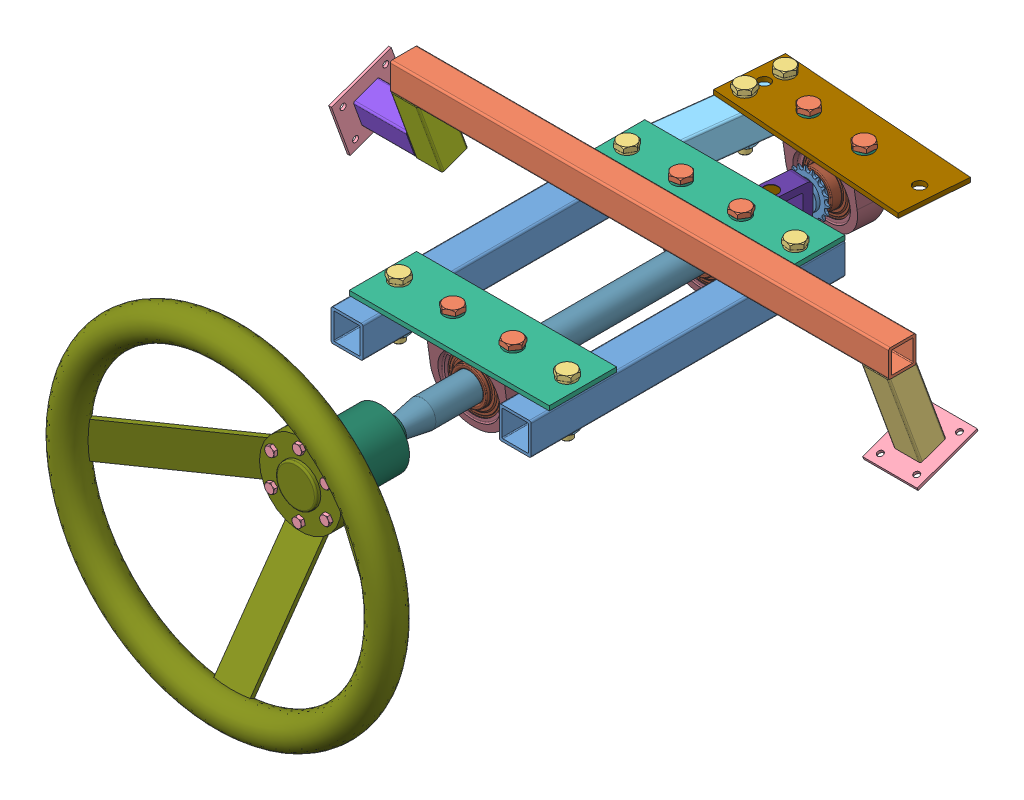
SolidWorks assembly Kolumna kierownicza uproszczenie, configuration Domyślna. Lengths in mm.
Overall size (624 386.49 780.76).
85 component instances, 24 part files, 119 mates.
Components (placement in the parent):
- belka nośna wzdłóżna-1: belka nośna wzdłóżna [Domyślna] at (-21.9242 46.9041 -172.5) size (35 35 345)
- belka nośna wzdłóżna-2: belka nośna wzdłóżna [Domyślna] at (163.0758 46.9041 -172.5) size (35 35 345)
- belka nośna poprzeczna-1: belka nośna poprzeczna [Domyślna] at (-192.6858 81.9041 -63.5) x (0 0 -1) z (1 0 0) size (30 30 548)
- belka wspornikowa pionowa-1: belka wspornikowa pionowa [Domyślna] at (352.3142 -9.754 -112.8235) x (0 0.34202 -0.939693) z (0 0.939693 0.34202) size (30 30 103)
- blacha mocująca-1: blacha mocująca [Domyślna] at (-250.6858 42.1744 -56.6769) x (0 0.34202 -0.939693) z (0 0.939693 0.34202) size (70 3 60)
- blacha mocująca-2: blacha mocująca [Domyślna] at (310.3142 -21.7247 -79.9342) x (0 0.34202 -0.939693) z (-1 0 0) size (70 3 60)
- brlka nośna skośna-1: brlka nośna skośna [Domyślna] at (12.5071 46.9041 -309.3237) x (0.992546 0 0.121869) z (-0.121869 0 0.992546) size (35 35 140)
- blacha nośna-1: blacha nośna [Domyślna] at (-21.9242 81.9041 152.5) size (220 5 74)
- blacha nośna-2: blacha nośna [Domyślna] at (-21.9242 81.9041 -98.5) size (220 5 74)
- belka wspornikowa pionowa mała-1: belka wspornikowa pionowa mała [Domyślna] at (-165.6858 11.859 -104.957) x (0 0.34202 -0.939693) z (0 0.939693 0.34202) size (30 30 80)
- belka poprzeczna mała-1: belka poprzeczna mała [Domyślna] at (-250.6858 16.9893 -119.0524) x (0 0.939693 0.34202) z (1 0 0) size (30 30 58)
- blacha nośna wachliwa-1: blacha nośna wachliwa [Domyślna] at (-12.9041 81.9041 -239.0734) x (0.997266 0 0.073897) z (-0.073897 0 0.997266) size (220 5 74)
- SKF_UCPA 206-1: SKF_UCPA 206 [Default] at (88.0758 39.1041 115.5) x (0 0 1) z (1 0 0) size (41.71 84.01 93.51)
  - 30-62-38.1-18-ucpa--9.525-46.5-1: 30-62-38.1-18-ucpa--9.525-46.5 [Default] at (0 39.6902 16.4402) x (1 0 0) z (0 0 -1) size (9.53 9.52 9.53)
  - 30-62-38.1-18-ucpa--9.525-46.5-2: 30-62-38.1-18-ucpa--9.525-46.5 [Default] at (0 23.25 23.25) x (1 0 0) z (0 0 -1) size (9.53 9.52 9.53)
  - 30-62-38.1-18-ucpa--9.525-46.5-3: 30-62-38.1-18-ucpa--9.525-46.5 [Default] at (0 6.8098 16.4402) x (1 0 0) z (0 0 -1) size (9.53 9.52 9.53)
  - 30-62-38.1-18-ucpa--9.525-46.5-4: 30-62-38.1-18-ucpa--9.525-46.5 [Default] x (1 0 0) z (0 0 -1) size (9.53 9.52 9.53)
  - 30-62-38.1-18-ucpa--9.525-46.5-5: 30-62-38.1-18-ucpa--9.525-46.5 [Default] at (0 6.8098 -16.4402) x (1 0 0) z (0 0 -1) size (9.53 9.52 9.53)
  - 30-62-38.1-18-ucpa--9.525-46.5-6: 30-62-38.1-18-ucpa--9.525-46.5 [Default] at (0 23.25 -23.25) x (1 0 0) z (0 0 -1) size (9.53 9.52 9.53)
  - 30-62-38.1-18-ucpa--9.525-46.5-7: 30-62-38.1-18-ucpa--9.525-46.5 [Default] at (0 39.6902 -16.4402) x (1 0 0) z (0 0 -1) size (9.53 9.52 9.53)
  - 30-62-38.1-18-ucpa--9.525-46.5-8: 30-62-38.1-18-ucpa--9.525-46.5 [Default] at (0 46.5 0) x (1 0 0) z (0 0 -1) size (9.53 9.52 9.53)
  - UC 206-39.862-b-1: UC 206-39.862-b [Default] x (-1 0 0) z (0 0 -1) size (38.1 62 62)
  - 1_4-28 UNF-1: 1_4-28 UNF [Default] at (-2.5 29.8399 29.8399) x (1 0 0) z (0 -0.707107 0.707107) size (9.18 13.9 9.18)
  - PA 206 -h-1: PA 206 -h [Domyślna] x (0 0 1) z (-1 0 0) size (93.51 84.01 39.21)
- SKF_UCPA 206-2: SKF_UCPA 206 [Default] at (88.0758 39.1041 -135.5) x (0 0 1) z (1 0 0) size (41.71 84.01 93.51)
  - 30-62-38.1-18-ucpa--9.525-46.5-1: 30-62-38.1-18-ucpa--9.525-46.5 [Default] at (0 39.6902 16.4402) x (1 0 0) z (0 0 -1) size (9.53 9.52 9.53)
  - 30-62-38.1-18-ucpa--9.525-46.5-2: 30-62-38.1-18-ucpa--9.525-46.5 [Default] at (0 23.25 23.25) x (1 0 0) z (0 0 -1) size (9.53 9.52 9.53)
  - 30-62-38.1-18-ucpa--9.525-46.5-3: 30-62-38.1-18-ucpa--9.525-46.5 [Default] at (0 6.8098 16.4402) x (1 0 0) z (0 0 -1) size (9.53 9.52 9.53)
  - 30-62-38.1-18-ucpa--9.525-46.5-4: 30-62-38.1-18-ucpa--9.525-46.5 [Default] x (1 0 0) z (0 0 -1) size (9.53 9.52 9.53)
  - 30-62-38.1-18-ucpa--9.525-46.5-5: 30-62-38.1-18-ucpa--9.525-46.5 [Default] at (0 6.8098 -16.4402) x (1 0 0) z (0 0 -1) size (9.53 9.52 9.53)
  - 30-62-38.1-18-ucpa--9.525-46.5-6: 30-62-38.1-18-ucpa--9.525-46.5 [Default] at (0 23.25 -23.25) x (1 0 0) z (0 0 -1) size (9.53 9.52 9.53)
  - 30-62-38.1-18-ucpa--9.525-46.5-7: 30-62-38.1-18-ucpa--9.525-46.5 [Default] at (0 39.6902 -16.4402) x (1 0 0) z (0 0 -1) size (9.53 9.52 9.53)
  - 30-62-38.1-18-ucpa--9.525-46.5-8: 30-62-38.1-18-ucpa--9.525-46.5 [Default] at (0 46.5 0) x (1 0 0) z (0 0 -1) size (9.53 9.52 9.53)
  - UC 206-39.862-b-1: UC 206-39.862-b [Default] x (-1 0 0) z (0 0 -1) size (38.1 62 62)
  - 1_4-28 UNF-1: 1_4-28 UNF [Default] at (-2.5 29.8399 29.8399) x (1 0 0) z (0 -0.707107 0.707107) size (9.18 13.9 9.18)
  - PA 206 -h-1: PA 206 -h [Domyślna] x (0 0 1) z (-1 0 0) size (93.51 84.01 39.21)
- SKF_UCPA 206-3: SKF_UCPA 206 [Default] at (93.0471 39.1041 -268.3239) x (0.073897 0 -0.997266) z (-0.997266 0 -0.073897) size (41.71 84.01 93.51)
  - 30-62-38.1-18-ucpa--9.525-46.5-1: 30-62-38.1-18-ucpa--9.525-46.5 [Default] at (0 39.6902 16.4402) x (1 0 0) z (0 0 -1) size (9.53 9.52 9.53)
  - 30-62-38.1-18-ucpa--9.525-46.5-2: 30-62-38.1-18-ucpa--9.525-46.5 [Default] at (0 23.25 23.25) x (1 0 0) z (0 0 -1) size (9.53 9.52 9.53)
  - 30-62-38.1-18-ucpa--9.525-46.5-3: 30-62-38.1-18-ucpa--9.525-46.5 [Default] at (0 6.8098 16.4402) x (1 0 0) z (0 0 -1) size (9.53 9.52 9.53)
  - 30-62-38.1-18-ucpa--9.525-46.5-4: 30-62-38.1-18-ucpa--9.525-46.5 [Default] x (1 0 0) z (0 0 -1) size (9.53 9.52 9.53)
  - 30-62-38.1-18-ucpa--9.525-46.5-5: 30-62-38.1-18-ucpa--9.525-46.5 [Default] at (0 6.8098 -16.4402) x (1 0 0) z (0 0 -1) size (9.53 9.52 9.53)
  - 30-62-38.1-18-ucpa--9.525-46.5-6: 30-62-38.1-18-ucpa--9.525-46.5 [Default] at (0 23.25 -23.25) x (1 0 0) z (0 0 -1) size (9.53 9.52 9.53)
  - 30-62-38.1-18-ucpa--9.525-46.5-7: 30-62-38.1-18-ucpa--9.525-46.5 [Default] at (0 39.6902 -16.4402) x (1 0 0) z (0 0 -1) size (9.53 9.52 9.53)
  - 30-62-38.1-18-ucpa--9.525-46.5-8: 30-62-38.1-18-ucpa--9.525-46.5 [Default] at (0 46.5 0) x (1 0 0) z (0 0 -1) size (9.53 9.52 9.53)
  - UC 206-39.862-b-1: UC 206-39.862-b [Default] x (-1 0 0) z (0 0 -1) size (38.1 62 62)
  - 1_4-28 UNF-1: 1_4-28 UNF [Default] at (-2.5 29.8399 29.8399) x (1 0 0) z (0 -0.707107 0.707107) size (9.18 13.9 9.18)
  - PA 206 -h-1: PA 206 -h [Domyślna] x (0 0 1) z (-1 0 0) size (93.51 84.01 39.21)
- Wał kierownicy-1: Wał kierownicy [Domyślna] at (88.0758 39.1041 -167.7352) x (0.999992 -0.003877 0) z (0 0 1) size (30 30 425)
- Naba-1: Naba [Domyślna] at (88.0758 39.1041 293.2648) x (0.999992 -0.003877 0) z (0 0 1) size (90 90 87)
- kierownica-1: kierownica [Domyślna] at (88.0758 39.1041 396.2648) x (-0.999992 0.003877 0) z (0 0 -1) size (385 385 172.09)
- widelec kardana-1: widelec kardana [Domyślna] at (88.0332 28.1042 -167.7352) x (0.999992 -0.003877 0) z (0.003877 0.999992 0) size (43 45 22)
- krzyżak kardana-1: krzyżak kardana [Domyślna] at (88.0758 39.1041 -201.2352) x (-0.000001 -0.000287 1) z (0.003877 0.999992 0.000287) size (15 42 42)
- widelec kardana-2: widelec kardana [Domyślna] at (79.5815 39.1469 -235.4564) x (0.003877 0.999992 0.000287) z (0.997258 -0.003888 0.073897) size (43 45 22)
- koło z18-1: koło z18 [Domyślna] at (90.95 39.1041 -240.0238) x (0.997259 -0.003686 0.073897) z (-0.073897 0 0.997266) size (50.17 49.75 54)
- śruba m12 l23-1: śruba m12 l23 [Domyślna] at (55.0758 89.4041 115.5) x (-0.820271 0 -0.571975) z (0.571975 0 -0.820271) size (24.13 28.5 19)
- śruba m12 l23-2: śruba m12 l23 [Domyślna] at (55.0758 89.4041 -135.5) x (0.666256 0 0.745723) z (-0.745723 0 0.666256) size (24.13 28.5 19)
- śruba m12 l23-3: śruba m12 l23 [Domyślna] at (121.0758 89.4041 115.5) x (0.439719 0 0.898135) z (-0.898135 0 0.439719) size (24.13 28.5 19)
- śruba m12 l23-4: śruba m12 l23 [Domyślna] at (121.0758 89.4041 -135.5) x (-0.999882 0 -0.015363) z (0.015363 0 -0.999882) size (24.13 28.5 19)
- śruba m12 l23-5: śruba m12 l23 [Domyślna] at (125.9569 89.4041 -265.8853) x (0.80948 0 0.587148) z (-0.587148 0 0.80948) size (24.13 28.5 19)
- śruba m12 l23-6: śruba m12 l23 [Domyślna] at (60.1373 89.4041 -270.7625) x (0.757641 0 0.652671) z (-0.652671 0 0.757641) size (24.13 28.5 19)
- śruba m12 l50-1: śruba m12 l50 [Domyślna] at (180.5758 89.4041 115.5) x (0.860091 0 -0.510141) z (0.510141 0 0.860091) size (24.13 65.5 19.5)
- śruba m12 l50-2: śruba m12 l50 [Domyślna] at (-4.4242 89.4041 115.5) x (-0.849457 0 0.527658) z (-0.527658 0 -0.849457) size (24.13 65.5 19.5)
- śruba m12 l50-3: śruba m12 l50 [Domyślna] at (180.5758 89.4041 -135.5) x (-0.992744 0 -0.120247) z (0.120247 0 -0.992744) size (24.13 65.5 19.5)
- śruba m12 l50-4: śruba m12 l50 [Domyślna] at (10.679 89.4041 -294.4356) x (0.616507 0 0.787349) z (-0.787349 0 0.616507) size (24.13 65.5 19.5)
- śruba m12 l50-5: śruba m12 l50 [Domyślna] at (-4.4242 89.4041 -135.5) x (0.477031 0 -0.878886) z (0.878886 0 0.477031) size (24.13 65.5 19.5)
- śruba m12 l50-6: śruba m12 l50 [Domyślna] at (5.8043 89.4041 -254.7337) x (0.730515 0 -0.682896) z (0.682896 0 0.730515) size (24.13 65.5 19.5)
- śruba m6 l20-1: śruba m6 l20 [Domyślna] at (57.6973 21.7217 316.2648) x (0.939662 0.342105 0) z (0.342105 -0.939662 0) size (12.7 34 10)
- śruba m6 l20-2: śruba m6 l20 [Domyślna] at (87.9401 4.1043 316.2648) x (0.702048 0.712129 0) z (0.712129 -0.702048 0) size (12.7 34 10)
- śruba m6 l20-3: śruba m6 l20 [Domyślna] at (118.3186 21.4867 316.2648) x (1 0 0) z (0 -1 0) size (12.7 34 10)
- śruba m6 l20-4: śruba m6 l20 [Domyślna] at (118.4543 56.4864 316.2648) x (0.461947 0.886907 0) z (0.886907 -0.461947 0) size (12.7 34 10)
- śruba m6 l20-5: śruba m6 l20 [Domyślna] at (57.833 56.7215 316.2648) x (0.888577 0.458728 0) z (0.458728 -0.888577 0) size (12.7 34 10)
- śruba m6 l20-6: śruba m6 l20 [Domyślna] at (88.2115 74.1038 316.2648) x (0.463667 0.886009 0) z (0.886009 -0.463667 0) size (12.7 34 10)
- nakrętka m12-1: nakrętka m12 [Domyślna] at (180.5758 41.4041 115.5) x (-0.992388 0 0.123152) z (-0.123152 0 -0.992388) size (19.5 8.5 21.94)
- nakrętka m12-2: nakrętka m12 [Domyślna] at (-4.4242 41.4041 115.5) x (0.996646 0 -0.081836) z (0.081836 0 0.996646) size (19.5 8.5 21.94)
- nakrętka m12-3: nakrętka m12 [Domyślna] at (-4.4242 41.4041 -135.5) x (0.999558 0 -0.029743) z (0.029743 0 0.999558) size (19.5 8.5 21.94)
- nakrętka m12-4: nakrętka m12 [Domyślna] at (5.8043 41.4041 -254.7337) x (0.999266 0 -0.038299) z (0.038299 0 0.999266) size (19.5 8.5 21.94)
- nakrętka m12-5: nakrętka m12 [Domyślna] at (10.679 41.4041 -294.4356) x (0.99796 0 -0.063845) z (0.063845 0 0.99796) size (19.5 8.5 21.94)
- nakrętka m12-6: nakrętka m12 [Domyślna] at (180.5758 41.4041 -135.5) size (19.5 8.5 21.94)
- nordlock m12-1: nordlock m12 [Domyślna] at (60.1373 86.9041 -270.7625) size (19.5 2.5 19.5)
- nordlock m12-2: nordlock m12 [Domyślna] at (121.0758 86.9041 115.5) size (19.5 2.5 19.5)
- nordlock m12-3: nordlock m12 [Domyślna] at (55.0758 86.9041 115.5) size (19.5 2.5 19.5)
- nordlock m12-4: nordlock m12 [Domyślna] at (121.0758 86.9041 -135.5) size (19.5 2.5 19.5)
- nordlock m12-5: nordlock m12 [Domyślna] at (55.0758 86.9041 -135.5) size (19.5 2.5 19.5)
- nordlock m12-6: nordlock m12 [Domyślna] at (125.9569 86.9041 -265.8853) size (19.5 2.5 19.5)
Mates (geometry in assembly coordinates):
- Odległość1: distance = 220 mm anti-aligned: plane of belka nośna wzdłóżna-1 through (-21.9242 48.9041 172.5) normal (-1 0 0); plane of belka nośna wzdłóżna-2 through (198.0758 48.9041 172.5) normal (1 0 0)
- Wspólnie2: coincident aligned: plane of belka nośna wzdłóżna-1 through (-19.9242 81.9041 172.5) normal (0 1 0); plane of belka nośna wzdłóżna-2 through (165.0758 81.9041 172.5) normal (0 1 0)
- Wspólnie3: coincident aligned: plane of belka nośna wzdłóżna-1 through (11.0758 48.9041 172.5) normal (0 0 1); plane of belka nośna wzdłóżna-2 through (196.0758 48.9041 172.5) normal (0 0 1)
- Wspólnie4: coincident anti-aligned: plane of belka nośna wzdłóżna-1 through (-19.9242 81.9041 172.5) normal (0 1 0); plane of belka nośna poprzeczna-1 through (355.3142 81.9041 -65.5) normal (0 -1 0)
- Wspólnie5: coincident anti-aligned: plane of belka nośna wzdłóżna-1 through (-19.9242 81.9041 172.5) normal (0 1 0); plane of blacha nośna-1 through (-21.9242 81.9041 152.5) normal (0 -1 0)
- Koncentryczne1: concentric aligned: circle of belka nośna wzdłóżna-2; circle of blacha nośna-1
- Odległość2: distance = 142 mm anti-aligned: plane of belka nośna poprzeczna-1 through (355.3142 83.9041 -63.5) normal (0 0 1); plane of blacha nośna-1 through (-21.9242 86.9041 78.5) normal (0 0 -1)
- Wspólnie9: coincident anti-aligned: plane of belka nośna wzdłóżna-2 through (165.0758 81.9041 172.5) normal (0 1 0); plane of blacha nośna-2 through (-21.9242 81.9041 -98.5) normal (0 -1 0)
- Koncentryczne3: concentric aligned: circle of belka nośna wzdłóżna-2; circle of blacha nośna-2
- Wspólnie12: coincident aligned: plane of belka nośna wzdłóżna-2 through (198.0758 48.9041 172.5) normal (1 0 0); plane of blacha nośna-2 through (198.0758 86.9041 -98.5) normal (1 0 0)
- Wspólnie13: coincident aligned: plane of belka nośna wzdłóżna-2 through (198.0758 48.9041 172.5) normal (1 0 0); plane of blacha nośna-1 through (198.0758 86.9041 152.5) normal (1 0 0)
- Wspólnie17: coincident anti-aligned: plane of belka nośna poprzeczna-1 through (355.3142 81.9041 -65.5) normal (0 -1 0); plane of belka wspornikowa pionowa-1 through (285.3142 81.9041 -63.5) normal (0 1 0)
- Wspólnie18: coincident aligned: plane of belka nośna poprzeczna-1 through (355.3142 83.9041 -65.5) normal (1 0 0); plane of belka wspornikowa pionowa-1 through (355.3142 82.5881 -65.3794) normal (1 0 0)
- Wspólnie19: coincident: plane of belka nośna poprzeczna-1 through (355.3142 83.9041 -63.5) normal (0 0 1); line of belka wspornikowa pionowa-1 through (327.3142 81.9041 -63.5) axis (1 0 0)
- Wspólnie20: coincident anti-aligned: plane of belka wspornikowa pionowa-1 through (353.3142 -14.2002 -100.6075) normal (0 -0.939693 -0.34202); plane of blacha mocująca-2 through (310.3142 -21.7247 -79.9342) normal (0 0.939693 0.34202)
- Odległość4: distance = 15 mm aligned: plane of belka wspornikowa pionowa-1 through (355.3142 82.5881 -65.3794) normal (1 0 0); plane of blacha mocująca-2 through (370.3142 -24.5437 -80.9603) normal (1 0 0)
- Odległość3: distance = 20 mm aligned: plane of blacha mocująca-2 through (310.3142 -24.5437 -80.9603) normal (0 -0.34202 0.939693); plane of belka wspornikowa pionowa-1 through (353.3142 81.9041 -63.5) normal (0 -0.34202 0.939693)
- Wspólnie25: coincident anti-aligned: plane of belka nośna wzdłóżna-1 through (11.0758 48.9041 -172.5) normal (0 0 -1); plane of brlka nośna skośna-1 through (-21.9242 -58.0959 -172.5) normal (0 0 1)
- Wspólnie26: coincident aligned: line of belka nośna wzdłóżna-1 through (-21.9242 79.9041 -172.5) axis (0 -1 0); line of brlka nośna skośna-1 through (-21.9242 79.9041 -172.5) axis (0 -1 0)
- Wspólnie27: coincident aligned: plane of belka nośna wzdłóżna-1 through (-19.9242 46.9041 172.5) normal (0 -1 0); plane of brlka nośna skośna-1 through (-19.9391 46.9041 -172.2563) normal (0 -1 0)
- Wspólnie28: coincident anti-aligned: plane of belka nośna poprzeczna-1 through (355.3142 81.9041 -65.5) normal (0 -1 0); plane of belka wspornikowa pionowa mała-1 through (-232.6858 81.9041 -63.5) normal (0 1 0)
- Wspólnie29: coincident aligned: plane of belka nośna poprzeczna-1 through (-192.6858 83.9041 -65.5) normal (-1 0 0); plane of belka wspornikowa pionowa mała-1 through (-192.6858 82.5881 -65.3794) normal (-1 0 0)
- Wspólnie30: coincident: plane of belka nośna poprzeczna-1 through (355.3142 83.9041 -63.5) normal (0 0 1); line of belka wspornikowa pionowa mała-1 through (-190.6858 81.9041 -63.5) axis (1 0 0)
- Wspólnie31: coincident anti-aligned: plane of belka wspornikowa pionowa mała-1 through (-192.6858 82.5881 -65.3794) normal (-1 0 0); plane of belka poprzeczna mała-1 through (-192.6858 18.1846 -116.489) normal (1 0 0)
- Wspólnie32: coincident aligned: plane of belka wspornikowa pionowa mała-1 through (-164.6858 81.9041 -63.5) normal (0 -0.34202 0.939693); plane of belka poprzeczna mała-1 through (-192.6858 8.6081 -90.1776) normal (0 -0.34202 0.939693)
- Wspólnie33: coincident aligned: plane of belka wspornikowa pionowa mała-1 through (-164.6858 7.4127 -92.741) normal (0 -0.939693 -0.34202); plane of belka poprzeczna mała-1 through (-192.6858 16.3052 -117.173) normal (0 -0.939693 -0.34202)
- Wspólnie34: coincident anti-aligned: plane of blacha mocująca-1 through (-250.6858 42.1744 -56.6769) normal (1 0 0); plane of belka poprzeczna mała-1 through (-250.6858 18.1846 -116.489) normal (-1 0 0)
- Odległość5: distance = 20 mm aligned: plane of blacha mocująca-1 through (-253.6858 42.1744 -56.6769) normal (0 -0.34202 0.939693); plane of belka poprzeczna mała-1 through (-192.6858 8.6081 -90.1776) normal (0 -0.34202 0.939693)
- Odległość6: distance = 15 mm aligned: plane of belka poprzeczna mała-1 through (-192.6858 44.496 -106.9124) normal (0 0.939693 0.34202); plane of blacha mocująca-1 through (-253.6858 42.1744 -56.6769) normal (0 0.939693 0.34202)
- Wspólnie37: coincident anti-aligned: plane of brlka nośna skośna-1 through (-19.9391 81.9041 -172.2563) normal (0 1 0); plane of blacha nośna wachliwa-1 through (-12.9041 81.9041 -239.0734) normal (0 -1 0)
- Koncentryczne4: concentric aligned: circle of brlka nośna skośna-1; circle of blacha nośna wachliwa-1
- Wspólnie39: coincident anti-aligned: plane of blacha nośna-1 through (-21.9242 81.9041 152.5) normal (0 -1 0); plane of SKF_UCPA 206-1/PA 206 -h-1 through (41.3258 81.9041 135) normal (0 1 0)
- Wspólnie40: coincident anti-aligned: plane of blacha nośna-2 through (-21.9242 81.9041 -98.5) normal (0 -1 0); plane of SKF_UCPA 206-3/PA 206 -h-1 through (82.4212 81.9041 -288.6647) normal (0 1 0)
- Wspólnie41: coincident anti-aligned: plane of blacha nośna wachliwa-1 through (-12.9041 81.9041 -239.0734) normal (0 -1 0); plane of SKF_UCPA 206-2/PA 206 -h-1 through (41.3258 81.9041 -116) normal (0 1 0)
- Koncentryczne5: concentric aligned: circle of blacha nośna-1; circle of SKF_UCPA 206-1/PA 206 -h-1
- Koncentryczne6: concentric aligned: circle of blacha nośna-2; circle of SKF_UCPA 206-2/PA 206 -h-1
- Koncentryczne7: concentric aligned: circle of SKF_UCPA 206-3/PA 206 -h-1; circle of blacha nośna wachliwa-1
- Koncentryczne8: concentric aligned: circle of SKF_UCPA 206-3/PA 206 -h-1; circle of blacha nośna wachliwa-1
- Koncentryczne9: concentric anti-aligned: cylinder of blacha nośna-2 through (55.0758 86.9041 -135.5) axis (0 -1 0) radius 6.5; cylinder of SKF_UCPA 206-2/PA 206 -h-1 through (55.0758 81.9041 -135.5) axis (0 1 0) radius 6
- Koncentryczne10: concentric anti-aligned: cylinder of blacha nośna-1 through (55.0758 86.9041 115.5) axis (0 -1 0) radius 6.5; cylinder of SKF_UCPA 206-1/PA 206 -h-1 through (55.0758 81.9041 115.5) axis (0 1 0) radius 6
- Wspólnie42: coincident anti-aligned: plane of Naba-1 through (88.0758 39.1041 301.2648) normal (0 0 1); plane of kierownica-1 through (88.0758 39.1041 301.2648) normal (0 0 -1)
- Wspólnie43: coincident anti-aligned: circle of Naba-1; circle of kierownica-1
- Koncentryczne11: concentric aligned: cylinder of Wał kierownicy-1 through (88.0758 39.1041 257.2648) axis (0 0 -1) radius 10; cylinder of Naba-1 through (88.0758 39.1041 310.2648) axis (0 0 -1) radius 10
- Koncentryczne12: concentric aligned: cylinder of Wał kierownicy-1 through (88.1262 52.104 225.2648) axis (-0.003877 -0.999992 0) radius 3; cylinder of Naba-1 through (88.1495 58.1039 225.2648) axis (-0.003877 -0.999992 0) radius 3
- Koncentryczne13: concentric anti-aligned: circle of Naba-1; circle of kierownica-1
- Koncentryczne14: concentric aligned: cylinder of SKF_UCPA 206-1/UC 206-39.862-b-1 through (88.0758 39.1041 65.5) axis (0 0 -1) radius 15; cylinder of Wał kierownicy-1 through (88.0758 39.1041 182.2648) axis (0 0 -1) radius 15
- Wspólnie44: coincident anti-aligned: plane of Wał kierownicy-1 through (88.0758 39.1041 -167.7352) normal (0 0 -1); plane of widelec kardana-1 through (66.6186 50.1874 -167.7352) normal (0 0 1)
- Koncentryczne15: concentric aligned: circle of Wał kierownicy-1; circle of widelec kardana-1
- Równolegle1: parallel aligned: plane of Wał kierownicy-1 through (88.1262 52.104 215.2648) normal (0.003877 0.999992 0); plane of widelec kardana-1 through (88.1185 50.104 -167.7352) normal (0.003877 0.999992 0)
- Koncentryczne16: concentric anti-aligned: cylinder of widelec kardana-1 through (46.5761 39.265 -201.2352) axis (0.999992 -0.003877 0) radius 7.5; cylinder of krzyżak kardana-1 through (109.0757 39.0227 -201.2352) axis (-0.999992 0.003877 0) radius 7.5
- Odległość7: distance = 0.5 mm aligned: plane of widelec kardana-1 through (109.6183 50.0206 -167.7352) normal (0.999992 -0.003877 0); plane of krzyżak kardana-1 through (109.0757 39.0227 -201.2352) normal (0.999992 -0.003877 0)
- Koncentryczne19: concentric anti-aligned: cylinder of krzyżak kardana-1 through (88.1572 60.1039 -201.2291) axis (-0.003877 -0.999992 -0.000287) radius 7.5; cylinder of widelec kardana-2 through (87.9149 -2.3956 -201.2471) axis (0.003877 0.999992 0.000287) radius 7.5
- Odległość8: distance = 0.5 mm aligned: plane of widelec kardana-2 through (101.4379 17.5615 -233.8369) normal (-0.003877 -0.999992 -0.000287); plane of krzyżak kardana-1 through (87.9944 18.1042 -201.2412) normal (-0.003877 -0.999992 -0.000287)
- Wspólnie48: coincident anti-aligned: plane of widelec kardana-2 through (101.4379 17.5615 -233.8369) normal (0.073897 0 -0.997266); plane of koło z18-1 through (90.5514 39.1041 -234.6436) normal (-0.073897 0 0.997266)
- Koncentryczne20: concentric anti-aligned: circle of widelec kardana-2; circle of koło z18-1
- Koncentryczne21: concentric anti-aligned: cylinder of SKF_UCPA 206-3/UC 206-39.862-b-1 through (89.3522 39.1041 -218.4606) axis (-0.073897 0 0.997266) radius 15; cylinder of koło z18-1 through (90.5514 39.1041 -234.6436) axis (0.073897 0 -0.997266) radius 15
- Koncentryczne22: concentric aligned: cylinder of SKF_UCPA 206-1/PA 206 -h-1 through (55.0758 81.9041 115.5) axis (0 1 0) radius 6; cylinder of śruba m12 l23-1 through (55.0758 66.4041 115.5) axis (0 1 0) radius 6
- Koncentryczne23: concentric aligned: cylinder of SKF_UCPA 206-1/PA 206 -h-1 through (121.0758 81.9041 115.5) axis (0 1 0) radius 6; cylinder of śruba m12 l23-3 through (121.0758 66.4041 115.5) axis (0 1 0) radius 6
- Wspólnie49: coincident aligned: circle of SKF_UCPA 206-2/PA 206 -h-1; cylinder of śruba m12 l23-2 through (55.0758 66.4041 -135.5) axis (0 1 0) radius 6
- Koncentryczne24: concentric aligned: cylinder of SKF_UCPA 206-2/PA 206 -h-1 through (121.0758 81.9041 -135.5) axis (0 1 0) radius 6; cylinder of śruba m12 l23-4 through (121.0758 66.4041 -135.5) axis (0 1 0) radius 6
- Koncentryczne25: concentric aligned: cylinder of SKF_UCPA 206-3/PA 206 -h-1 through (60.1373 81.9041 -270.7625) axis (0 1 0) radius 6; cylinder of śruba m12 l23-6 through (60.1373 66.4041 -270.7625) axis (0 1 0) radius 6
- Koncentryczne26: concentric aligned: cylinder of SKF_UCPA 206-3/PA 206 -h-1 through (125.9569 81.9041 -265.8853) axis (0 1 0) radius 6; cylinder of śruba m12 l23-5 through (125.9569 66.4041 -265.8853) axis (0 1 0) radius 6
- Koncentryczne27: concentric anti-aligned: cylinder of blacha nośna-1 through (-4.4242 86.9041 115.5) axis (0 -1 0) radius 6.5; cylinder of śruba m12 l50-2 through (-4.4242 29.4041 115.5) axis (0 1 0) radius 6
- Koncentryczne28: concentric anti-aligned: cylinder of blacha nośna-1 through (180.5758 86.9041 115.5) axis (0 -1 0) radius 6.5; cylinder of śruba m12 l50-1 through (180.5758 29.4041 115.5) axis (0 1 0) radius 6
- Koncentryczne29: concentric anti-aligned: cylinder of blacha nośna-2 through (-4.4242 86.9041 -135.5) axis (0 -1 0) radius 6.5; cylinder of śruba m12 l50-5 through (-4.4242 29.4041 -135.5) axis (0 1 0) radius 6
- Koncentryczne30: concentric aligned: circle of blacha nośna-2; cylinder of śruba m12 l50-3 through (180.5758 29.4041 -135.5) axis (0 1 0) radius 6
- Koncentryczne31: concentric anti-aligned: cylinder of blacha nośna wachliwa-1 through (5.8043 86.9041 -254.7337) axis (0 -1 0) radius 6.5; cylinder of śruba m12 l50-6 through (5.8043 29.4041 -254.7337) axis (0 1 0) radius 6
- Koncentryczne32: concentric aligned: cylinder of brlka nośna skośna-1 through (10.679 -58.0959 -294.4356) axis (0 1 0) radius 6.5; cylinder of śruba m12 l50-4 through (10.679 29.4041 -294.4356) axis (0 1 0) radius 6
- Koncentryczne44: concentric aligned: cylinder of kierownica-1 through (88.2115 74.1038 301.2648) axis (0 0 1) radius 3.5; cylinder of śruba m6 l20-6 through (88.2115 74.1038 286.2648) axis (0 0 1) radius 3
- Koncentryczne45: concentric aligned: cylinder of kierownica-1 through (57.833 56.7215 301.2648) axis (0 0 1) radius 3.5; cylinder of śruba m6 l20-5 through (57.833 56.7215 286.2648) axis (0 0 1) radius 3
- Koncentryczne46: concentric aligned: cylinder of kierownica-1 through (118.4543 56.4864 301.2648) axis (0 0 1) radius 3.5; cylinder of śruba m6 l20-4 through (118.4543 56.4864 286.2648) axis (0 0 1) radius 3
- Koncentryczne47: concentric aligned: cylinder of kierownica-1 through (57.6973 21.7217 301.2648) axis (0 0 1) radius 3.5; cylinder of śruba m6 l20-1 through (57.6973 21.7217 286.2648) axis (0 0 1) radius 3
- Koncentryczne48: concentric aligned: cylinder of kierownica-1 through (87.9401 4.1043 301.2648) axis (0 0 1) radius 3.5; cylinder of śruba m6 l20-2 through (87.9401 4.1043 286.2648) axis (0 0 1) radius 3
- Koncentryczne49: concentric aligned: cylinder of kierownica-1 through (118.3186 21.4867 301.2648) axis (0 0 1) radius 3.5; cylinder of śruba m6 l20-3 through (118.3186 21.4867 286.2648) axis (0 0 1) radius 3
- Wspólnie62: coincident anti-aligned: plane of kierownica-1 through (88.0758 39.1041 316.2648) normal (0 0 1); plane of śruba m6 l20-3 through (118.3186 21.4867 316.2648) normal (0 0 -1)
- Wspólnie63: coincident anti-aligned: plane of kierownica-1 through (88.0758 39.1041 316.2648) normal (0 0 1); plane of śruba m6 l20-4 through (118.4543 56.4864 316.2648) normal (0 0 -1)
- Wspólnie64: coincident anti-aligned: plane of kierownica-1 through (88.0758 39.1041 316.2648) normal (0 0 1); plane of śruba m6 l20-6 through (88.2115 74.1038 316.2648) normal (0 0 -1)
- Wspólnie65: coincident anti-aligned: plane of kierownica-1 through (88.0758 39.1041 316.2648) normal (0 0 1); plane of śruba m6 l20-5 through (57.833 56.7215 316.2648) normal (0 0 -1)
- Wspólnie66: coincident anti-aligned: plane of kierownica-1 through (88.0758 39.1041 316.2648) normal (0 0 1); plane of śruba m6 l20-1 through (57.6973 21.7217 316.2648) normal (0 0 -1)
- Wspólnie67: coincident anti-aligned: plane of kierownica-1 through (88.0758 39.1041 316.2648) normal (0 0 1); plane of śruba m6 l20-2 through (87.9401 4.1043 316.2648) normal (0 0 -1)
- Kąt1: planar angle = 3.189801 rad anti-aligned: plane of blacha nośna wachliwa-1 through (-12.9041 86.9041 -239.0734) normal (-0.997266 0 -0.073897); plane of brlka nośna skośna-1 through (-21.9242 48.9041 -172.5) normal (-0.992546 0 -0.121869)
- Koncentryczne50: concentric anti-aligned: cylinder of śruba m12 l50-1 through (180.5758 29.4041 115.5) axis (0 1 0) radius 6; cylinder of nakrętka m12-1 through (180.5758 44.4041 115.5) axis (0 -1 0) radius 6
- Koncentryczne51: concentric anti-aligned: cylinder of śruba m12 l50-5 through (-4.4242 29.4041 -135.5) axis (0 1 0) radius 6; cylinder of nakrętka m12-3 through (-4.4242 44.4041 -135.5) axis (0 -1 0) radius 6
- Koncentryczne52: concentric anti-aligned: cylinder of śruba m12 l50-3 through (180.5758 29.4041 -135.5) axis (0 1 0) radius 6; cylinder of nakrętka m12-6 through (180.5758 44.4041 -135.5) axis (0 -1 0) radius 6
- Koncentryczne53: concentric anti-aligned: cylinder of śruba m12 l50-2 through (-4.4242 29.4041 115.5) axis (0 1 0) radius 6; cylinder of nakrętka m12-2 through (-4.4242 44.4041 115.5) axis (0 -1 0) radius 6
- Koncentryczne54: concentric anti-aligned: cylinder of śruba m12 l50-6 through (5.8043 29.4041 -254.7337) axis (0 1 0) radius 6; cylinder of nakrętka m12-4 through (5.8043 44.4041 -254.7337) axis (0 -1 0) radius 6
- Koncentryczne55: concentric anti-aligned: cylinder of śruba m12 l50-4 through (10.679 29.4041 -294.4356) axis (0 1 0) radius 6; cylinder of nakrętka m12-5 through (10.679 44.4041 -294.4356) axis (0 -1 0) radius 6
- Wspólnie68: coincident anti-aligned: plane of belka nośna wzdłóżna-1 through (-19.9242 46.9041 172.5) normal (0 -1 0); plane of nakrętka m12-2 through (-4.4242 46.9041 115.5) normal (0 1 0)
- Wspólnie69: coincident anti-aligned: plane of belka nośna wzdłóżna-1 through (-19.9242 46.9041 172.5) normal (0 -1 0); plane of nakrętka m12-3 through (-4.4242 46.9041 -135.5) normal (0 1 0)
- Wspólnie70: coincident anti-aligned: plane of brlka nośna skośna-1 through (-19.9391 46.9041 -172.2563) normal (0 -1 0); plane of nakrętka m12-4 through (5.8043 46.9041 -254.7337) normal (0 1 0)
- Wspólnie71: coincident anti-aligned: plane of brlka nośna skośna-1 through (-19.9391 46.9041 -172.2563) normal (0 -1 0); plane of nakrętka m12-5 through (10.679 46.9041 -294.4356) normal (0 1 0)
- Wspólnie72: coincident anti-aligned: plane of belka nośna wzdłóżna-2 through (165.0758 46.9041 172.5) normal (0 -1 0); plane of nakrętka m12-1 through (180.5758 46.9041 115.5) normal (0 1 0)
- Wspólnie73: coincident anti-aligned: plane of belka nośna wzdłóżna-2 through (165.0758 46.9041 172.5) normal (0 -1 0); plane of nakrętka m12-6 through (180.5758 46.9041 -135.5) normal (0 1 0)
- Wspólnie74: coincident anti-aligned: plane of blacha nośna-1 through (-21.9242 86.9041 152.5) normal (0 1 0); plane of śruba m12 l50-1 through (180.5758 86.9041 115.5) normal (0 -1 0)
- Wspólnie75: coincident anti-aligned: plane of blacha nośna-1 through (-21.9242 86.9041 152.5) normal (0 1 0); plane of śruba m12 l50-2 through (-4.4242 86.9041 115.5) normal (0 -1 0)
- Wspólnie76: coincident anti-aligned: plane of blacha nośna-2 through (-21.9242 86.9041 -98.5) normal (0 1 0); plane of śruba m12 l50-3 through (180.5758 86.9041 -135.5) normal (0 -1 0)
- Wspólnie77: coincident anti-aligned: plane of blacha nośna wachliwa-1 through (-12.9041 86.9041 -239.0734) normal (0 1 0); plane of śruba m12 l50-4 through (10.679 86.9041 -294.4356) normal (0 -1 0)
- Wspólnie78: coincident anti-aligned: plane of blacha nośna wachliwa-1 through (-12.9041 86.9041 -239.0734) normal (0 1 0); plane of śruba m12 l50-6 through (5.8043 86.9041 -254.7337) normal (0 -1 0)
- Wspólnie79: coincident anti-aligned: plane of blacha nośna-2 through (-21.9242 86.9041 -98.5) normal (0 1 0); plane of śruba m12 l50-5 through (-4.4242 86.9041 -135.5) normal (0 -1 0)
- Wspólnie81: coincident anti-aligned: plane of śruba m12 l23-3 through (121.0758 89.4041 115.5) normal (0 -1 0); plane of nordlock m12-2 through (121.0758 89.4041 115.5) normal (0 1 0)
- Koncentryczne56: concentric anti-aligned: cylinder of śruba m12 l23-3 through (121.0758 66.4041 115.5) axis (0 1 0) radius 6; cylinder of nordlock m12-2 through (121.0758 89.4041 115.5) axis (0 -1 0) radius 9.75
- Wspólnie82: coincident anti-aligned: plane of blacha nośna-1 through (-21.9242 86.9041 152.5) normal (0 1 0); plane of nordlock m12-2 through (121.0758 86.9041 115.5) normal (0 -1 0)
- Wspólnie83: coincident anti-aligned: plane of śruba m12 l23-1 through (55.0758 89.4041 115.5) normal (0 -1 0); plane of nordlock m12-3 through (55.0758 89.4041 115.5) normal (0 1 0)
- Koncentryczne57: concentric anti-aligned: cylinder of śruba m12 l23-1 through (55.0758 66.4041 115.5) axis (0 1 0) radius 6; cylinder of nordlock m12-3 through (55.0758 89.4041 115.5) axis (0 -1 0) radius 6.5
- Wspólnie84: coincident anti-aligned: plane of blacha nośna-1 through (-21.9242 86.9041 152.5) normal (0 1 0); plane of nordlock m12-3 through (55.0758 86.9041 115.5) normal (0 -1 0)
- Koncentryczne58: concentric anti-aligned: cylinder of śruba m12 l23-4 through (121.0758 66.4041 -135.5) axis (0 1 0) radius 6; cylinder of nordlock m12-4 through (121.0758 89.4041 -135.5) axis (0 -1 0) radius 6.5
- Wspólnie85: coincident anti-aligned: plane of śruba m12 l23-4 through (121.0758 89.4041 -135.5) normal (0 -1 0); plane of nordlock m12-4 through (121.0758 89.4041 -135.5) normal (0 1 0)
- Wspólnie86: coincident anti-aligned: plane of blacha nośna-2 through (-21.9242 86.9041 -98.5) normal (0 1 0); plane of nordlock m12-4 through (121.0758 86.9041 -135.5) normal (0 -1 0)
- Koncentryczne59: concentric anti-aligned: cylinder of śruba m12 l23-2 through (55.0758 66.4041 -135.5) axis (0 1 0) radius 6; cylinder of nordlock m12-5 through (55.0758 89.4041 -135.5) axis (0 -1 0) radius 6.5
- Wspólnie87: coincident anti-aligned: plane of śruba m12 l23-2 through (55.0758 89.4041 -135.5) normal (0 -1 0); plane of nordlock m12-5 through (55.0758 89.4041 -135.5) normal (0 1 0)
- Wspólnie88: coincident anti-aligned: plane of blacha nośna-2 through (-21.9242 86.9041 -98.5) normal (0 1 0); plane of nordlock m12-5 through (55.0758 86.9041 -135.5) normal (0 -1 0)
- Koncentryczne60: concentric anti-aligned: cylinder of śruba m12 l23-6 through (60.1373 66.4041 -270.7625) axis (0 1 0) radius 6; cylinder of nordlock m12-1 through (60.1373 89.4041 -270.7625) axis (0 -1 0) radius 6.5
- Wspólnie89: coincident anti-aligned: plane of śruba m12 l23-6 through (60.1373 89.4041 -270.7625) normal (0 -1 0); plane of nordlock m12-1 through (60.1373 89.4041 -270.7625) normal (0 1 0)
- Wspólnie90: coincident anti-aligned: plane of blacha nośna wachliwa-1 through (-12.9041 86.9041 -239.0734) normal (0 1 0); plane of nordlock m12-1 through (60.1373 86.9041 -270.7625) normal (0 -1 0)
- Wspólnie91: coincident anti-aligned: plane of śruba m12 l23-5 through (125.9569 89.4041 -265.8853) normal (0 -1 0); plane of nordlock m12-6 through (125.9569 89.4041 -265.8853) normal (0 1 0)
- Koncentryczne61: concentric anti-aligned: cylinder of śruba m12 l23-5 through (125.9569 66.4041 -265.8853) axis (0 1 0) radius 6; cylinder of nordlock m12-6 through (125.9569 89.4041 -265.8853) axis (0 -1 0) radius 6.5
- Wspólnie92: coincident anti-aligned: plane of blacha nośna wachliwa-1 through (-12.9041 86.9041 -239.0734) normal (0 1 0); plane of nordlock m12-6 through (125.9569 86.9041 -265.8853) normal (0 -1 0)
- Wspólnie93: coincident anti-aligned: plane of Wał kierownicy-1 through (85.1262 52.1156 215.2648) normal (-0.999992 0.003877 0); plane of Naba-1 through (85.1495 58.1156 207.6748) normal (0.999992 -0.003877 0)
- Wspólnie94: coincident anti-aligned: plane of Wał kierownicy-1 through (91.0254 26.0926 215.2648) normal (0.999992 -0.003877 0); plane of Naba-1 through (91.1495 58.0923 207.6748) normal (-0.999992 0.003877 0)
